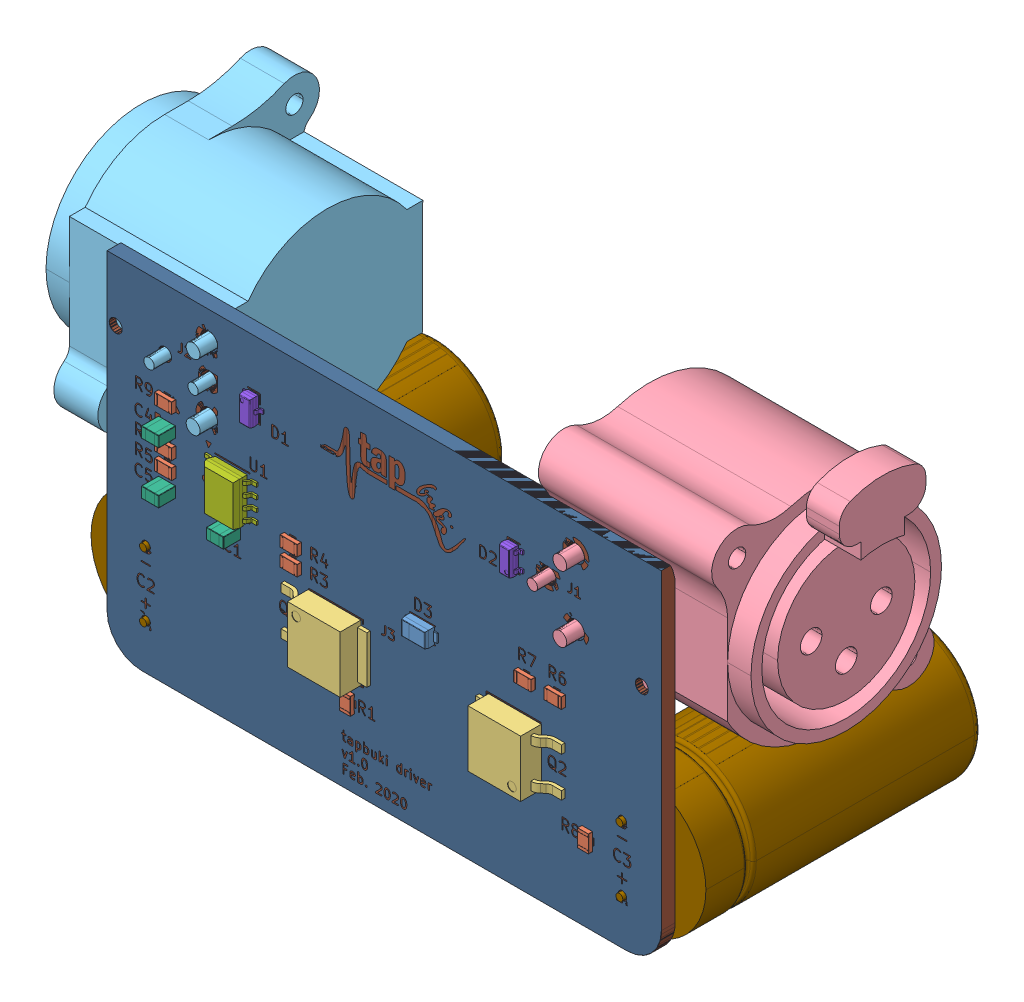
SolidWorks assembly kabuki-pcb-asm, configuration Standard. Lengths in mm.
Overall size (174.7 99.65 36.1).
46 component instances, 11 part files, 3 mates.
Components (placement in the parent):
- SODFL_SS1FH6^kabuki-pcb-asm-1: SODFL_SS1FH6^kabuki-pcb-asm [Standard] at (36.46 -19.555 1.65) x (1 0 0) z (0 -1 0) size (3.7 1.08 1.81) (virtual)
  - COMPOUND^SODFL_SS1FH6_kabuki-pcb-asm-1: COMPOUND^SODFL_SS1FH6_kabuki-pcb-asm [Standard] at origin size (3.7 1.08 1.81) (virtual)
- RES0805^kabuki-pcb-asm-1: RES0805^kabuki-pcb-asm [Standard] at (7 -11.5 1.65) x (1 0 0) z (0 -1 0) size (2 0.51 1.26) (virtual)
  - COMPOUND-0^RES0805_kabuki-pcb-asm-1: COMPOUND-0^RES0805_kabuki-pcb-asm [Standard] at origin size (2 0.51 1.26) (virtual)
- DPAK4P229_FQD18N20V2^kabuki-pcb-asm-1: DPAK4P229_FQD18N20V2^kabuki-pcb-asm [Standard] at (47.97 -25.5 1.65) x (0 1 0) z (1 0 0) size (6.54 2.39 9.91) (virtual)
  - COMPOUND-1^DPAK4P229_FQD18N20V2_kabuki-pcb-asm-1: COMPOUND-1^DPAK4P229_FQD18N20V2_kabuki-pcb-asm [Standard] at origin size (6.54 2.39 9.91) (virtual)
- RES0805^kabuki-pcb-asm-2: RES0805^kabuki-pcb-asm [Standard] at (55.5 -31 1.65) x (0 1 0) z (1 0 0) size (2 0.51 1.26) (virtual)
  - COMPOUND-0^RES0805_kabuki-pcb-asm-1: COMPOUND-0^RES0805_kabuki-pcb-asm [Standard] at origin size (2 0.51 1.26) (virtual)
- DPAK4P229_FQD18N20V2^kabuki-pcb-asm-2: DPAK4P229_FQD18N20V2^kabuki-pcb-asm [Standard] at (25.49 -25.5 1.65) x (0 -1 0) z (-1 0 0) size (6.54 2.39 9.91) (virtual)
  - COMPOUND-1^DPAK4P229_FQD18N20V2_kabuki-pcb-asm-1: COMPOUND-1^DPAK4P229_FQD18N20V2_kabuki-pcb-asm [Standard] at origin size (6.54 2.39 9.91) (virtual)
- nc3fahl1-1^kabuki-pcb-asm-1: nc3fahl1-1^kabuki-pcb-asm [Standard] at (70 -7 -11.05) x (0 0 1) z (-1 0 0) size (27.35 29.5 26.9) (virtual)
  - SOLID^nc3fahl1-1_kabuki-pcb-asm-1: SOLID^nc3fahl1-1_kabuki-pcb-asm [Standard] at origin size (27.35 29.5 26.9) (virtual)
- d-nc3mahr^kabuki-pcb-asm-1: d-nc3mahr^kabuki-pcb-asm [Standard] at (-6 -7 -11.05) x (0 0 -1) z (1 0 0) size (27.3 25.6 21.5) (virtual)
  - SOLID-2^d-nc3mahr_kabuki-pcb-asm-1: SOLID-2^d-nc3mahr_kabuki-pcb-asm [Standard] at origin size (27.3 25.6 21.5) (virtual)
- RES0805^kabuki-pcb-asm-3: RES0805^kabuki-pcb-asm [Standard] at (48.5 -18.5 1.65) x (-1 0 0) z (0 1 0) size (2 0.51 1.26) (virtual)
  - COMPOUND-0^RES0805_kabuki-pcb-asm-1: COMPOUND-0^RES0805_kabuki-pcb-asm [Standard] at origin size (2 0.51 1.26) (virtual)
- RES0805^kabuki-pcb-asm-4: RES0805^kabuki-pcb-asm [Standard] at (52 -18.5 1.65) x (-1 0 0) z (0 1 0) size (2 0.51 1.26) (virtual)
  - COMPOUND-0^RES0805_kabuki-pcb-asm-1: COMPOUND-0^RES0805_kabuki-pcb-asm [Standard] at origin size (2 0.51 1.26) (virtual)
- RES0805^kabuki-pcb-asm-5: RES0805^kabuki-pcb-asm [Standard] at (7 -18.111 1.65) x (-1 0 0) z (0 1 0) size (2 0.51 1.26) (virtual)
  - COMPOUND-0^RES0805_kabuki-pcb-asm-1: COMPOUND-0^RES0805_kabuki-pcb-asm [Standard] at origin size (2 0.51 1.26) (virtual)
- RES0805^kabuki-pcb-asm-6: RES0805^kabuki-pcb-asm [Standard] at (21.5 -18.5 1.65) x (1 0 0) z (0 -1 0) size (2 0.51 1.26) (virtual)
  - COMPOUND-0^RES0805_kabuki-pcb-asm-1: COMPOUND-0^RES0805_kabuki-pcb-asm [Standard] at origin size (2 0.51 1.26) (virtual)
- RES0805^kabuki-pcb-asm-7: RES0805^kabuki-pcb-asm [Standard] at (21.5 -20.5 1.65) x (1 0 0) z (0 -1 0) size (2 0.51 1.26) (virtual)
  - COMPOUND-0^RES0805_kabuki-pcb-asm-1: COMPOUND-0^RES0805_kabuki-pcb-asm [Standard] at origin size (2 0.51 1.26) (virtual)
- CAP0805^kabuki-pcb-asm-1: CAP0805^kabuki-pcb-asm [Standard] at (7 -20.111 1.65) x (1 0 0) z (0 -1 0) size (2 2 1.25) (virtual)
  - COMPOUND-3^CAP0805_kabuki-pcb-asm-1: COMPOUND-3^CAP0805_kabuki-pcb-asm [Standard] at origin size (2 2 1.25) (virtual)
- CAP0805^kabuki-pcb-asm-2: CAP0805^kabuki-pcb-asm [Standard] at (7 -14.111 1.65) x (1 0 0) z (0 -1 0) size (2 2 1.25) (virtual)
  - COMPOUND-3^CAP0805_kabuki-pcb-asm-1: COMPOUND-3^CAP0805_kabuki-pcb-asm [Standard] at origin size (2 2 1.25) (virtual)
- SOIC8P127_IX44XX^kabuki-pcb-asm-1: SOIC8P127_IX44XX^kabuki-pcb-asm [Standard] at (14.5 -16.5 1.65) x (0 -1 0) z (-1 0 0) size (4.91 1.75 6) (virtual)
  - COMPOUND-4^SOIC8P127_IX44XX_kabuki-pcb-asm-1: COMPOUND-4^SOIC8P127_IX44XX_kabuki-pcb-asm [Standard] at origin size (4.91 1.75 6) (virtual)
- RES0805^kabuki-pcb-asm-8: RES0805^kabuki-pcb-asm [Standard] at (7 -16.111 1.65) x (-1 0 0) z (0 1 0) size (2 0.51 1.26) (virtual)
  - COMPOUND-0^RES0805_kabuki-pcb-asm-1: COMPOUND-0^RES0805_kabuki-pcb-asm [Standard] at origin size (2 0.51 1.26) (virtual)
- RES0805^kabuki-pcb-asm-9: RES0805^kabuki-pcb-asm [Standard] at (28 -31 1.65) x (0 -1 0) z (-1 0 0) size (2 0.51 1.26) (virtual)
  - COMPOUND-0^RES0805_kabuki-pcb-asm-1: COMPOUND-0^RES0805_kabuki-pcb-asm [Standard] at origin size (2 0.51 1.26) (virtual)
- SOT23-3P95_MMBZxxxALT1G^kabuki-pcb-asm-1: SOT23-3P95_MMBZxxxALT1G^kabuki-pcb-asm [Standard] at (47 -7 1.65) x (0 1 0) z (1 0 0) size (2.93 1.12 2.37) (virtual)
  - COMPOUND-5^SOT23-3P95_MMBZxxxALT1G_kabuki-pcb-asm-1: COMPOUND-5^SOT23-3P95_MMBZxxxALT1G_kabuki-pcb-asm [Standard] at origin size (2.93 1.12 2.37) (virtual)
- SOT23-3P95_MMBZxxxALT1G^kabuki-pcb-asm-2: SOT23-3P95_MMBZxxxALT1G^kabuki-pcb-asm [Standard] at (17 -7 1.65) x (0 -1 0) z (-1 0 0) size (2.93 1.12 2.37) (virtual)
  - COMPOUND-5^SOT23-3P95_MMBZxxxALT1G_kabuki-pcb-asm-1: COMPOUND-5^SOT23-3P95_MMBZxxxALT1G_kabuki-pcb-asm [Standard] at origin size (2.93 1.12 2.37) (virtual)
- CAPPRD750W80D1600H3200^kabuki-pcb-asm-1: CAPPRD750W80D1600H3200^kabuki-pcb-asm [Standard] at (59.5 -31 -0.05) x (0 1 0) z (-1 0 0) size (16.01 34.01 16) (virtual)
  - COMPOUND-6^CAPPRD750W80D1600H3200_kabuki-pcb-asm-1: COMPOUND-6^CAPPRD750W80D1600H3200_kabuki-pcb-asm [Standard] at origin size (16.01 34.01 16) (virtual)
- CAPPRD750W80D1600H3200^kabuki-pcb-asm-2: CAPPRD750W80D1600H3200^kabuki-pcb-asm [Standard] at (4.5 -31 -0.05) x (0 1 0) z (-1 0 0) size (16.01 34.01 16) (virtual)
  - COMPOUND-6^CAPPRD750W80D1600H3200_kabuki-pcb-asm-1: COMPOUND-6^CAPPRD750W80D1600H3200_kabuki-pcb-asm [Standard] at origin size (16.01 34.01 16) (virtual)
- CAP0805^kabuki-pcb-asm-3: CAP0805^kabuki-pcb-asm [Standard] at (14.5 -20.5 1.65) x (-1 0 0) z (0 1 0) size (2 2 1.25) (virtual)
  - COMPOUND-3^CAP0805_kabuki-pcb-asm-1: COMPOUND-3^CAP0805_kabuki-pcb-asm [Standard] at origin size (2 2 1.25) (virtual)
- COMPOUND-7^kabuki-pcb-asm-1: COMPOUND-7^kabuki-pcb-asm [Standard] at origin size (64 40 1.6) (hidden, virtual)
- kabuki-pcb-1: kabuki-pcb [Standard] at (-102 50 0.7875) size (64 40 1.67)
Mates (geometry in assembly coordinates):
- Deckungsgleich1: coincident aligned: plane of COMPOUND-7^kabuki-pcb-1 through (0 0 0) normal (0 1 0); plane of kabuki-pcb-1 through (-102 0 0.7875) normal (0 1 0)
- Deckungsgleich2: coincident aligned: plane of COMPOUND-7^kabuki-pcb-1 through (0 -36 0) normal (-1 0 0); plane of kabuki-pcb-1 through (0 50 0.7875) normal (-1 0 0)
- Deckungsgleich3: coincident aligned: plane of COMPOUND-7^kabuki-pcb-1 through (32 -19.6365 0) normal (0 0 -1); plane of kabuki-pcb-1 through (-102 50 0) normal (0 0 -1)
